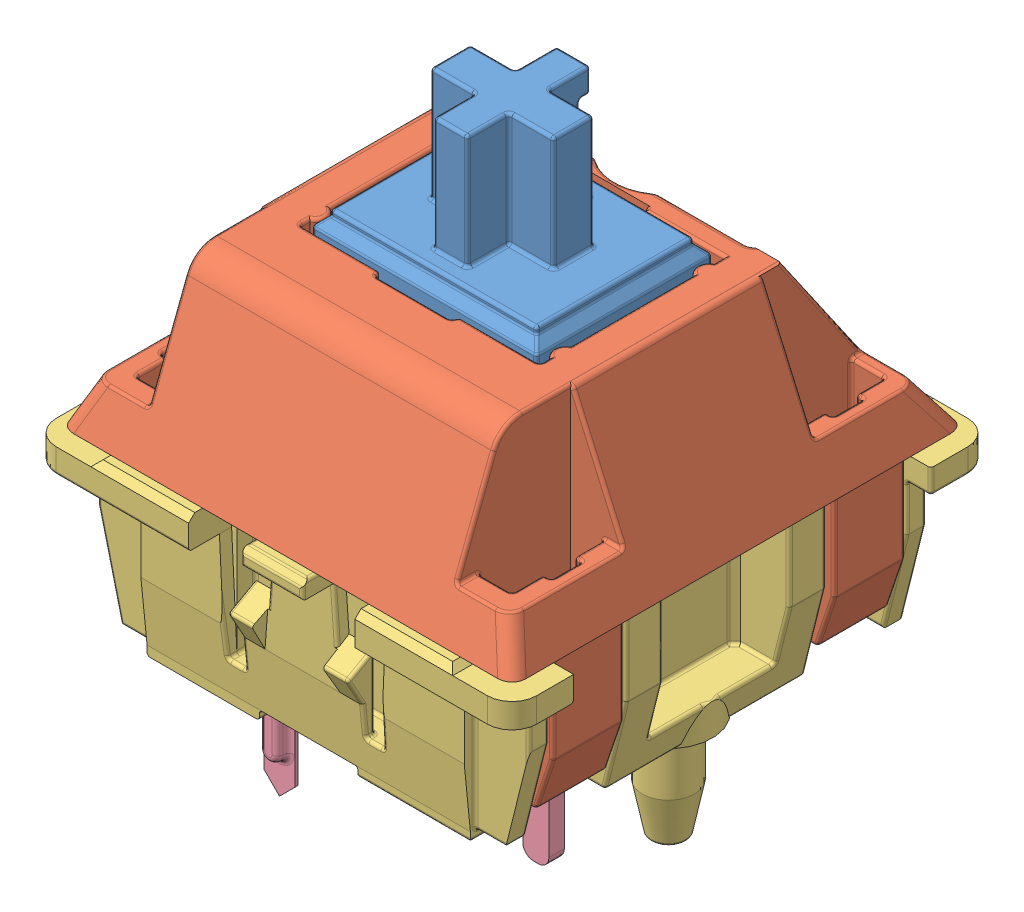
SolidWorks assembly MX_Switch, configuration Default. Lengths in mm.
Overall size (15.6 18.6 15.6).
4 component instances, 4 part files, 9 mates.
Components (placement in the parent):
- MX_Cross-1: MX_Cross [Default] at (7.35 2 -7.35) size (8.9 10.4 5.7)
- MX_Housing-1: MX_Housing [Default] at origin size (14.7 9.91 14.7)
- MX_bot-1: MX_bot [默认] at (7.35 -0.2 -7.35) size (15.6 12.5 15.6)
- MX_Pins-2: MX_Pins [默认] at (-5.5727 -8.7 12.741) size (7.15 6.7 2.96)
Mates (geometry in assembly coordinates):
- Distance1: distance = 0.15 mm anti-aligned: plane of MX 轴 轴体-1 through (3.45 1.4 -4.35) normal (0 0 -1); plane of MX_Cross-1 through (3.7 5.2 -4.5) normal (0 0 1)
- Distance2: distance = 0.25 mm anti-aligned: plane of MX 轴 轴体-1 through (3.45 1.4 -10.35) normal (1 0 0); plane of MX_Cross-1 through (3.7 5.2 -10.2) normal (-1 0 0)
- Coincident4: coincident anti-aligned: plane of MX 轴 轴体-1 through (0 0 0) normal (0 -1 0); plane of MX_bot-1 through (7.35 0 -7.35) normal (0 1 0)
- LimitDistance2: limit distance = -0.5 mm aligned: plane of MX_Cross-1 through (7.35 5.7 -7.35) normal (0 1 0); plane of MX 轴 轴体-1 through (0 5.2 0) normal (0 1 0)
- Coincident10: coincident anti-aligned: plane of MX_bot-1 through (10.6 -0.9 -4.95) normal (0 0 1); plane of 针脚-2 through (10.6 -2.5 -4.95) normal (0 0 -1)
- Coincident11: coincident anti-aligned: plane of MX_bot-1 through (10.6 -0.9 -4.95) normal (1 0 0); plane of 针脚-2 through (10.6 -2.5 -4.95) normal (-1 0 0)
- Concentric1: concentric anti-aligned: cylinder of MX 轴 轴体-1 through (7.35 0.5 -12.292) axis (0 1 0) radius 1.6; cylinder of MX_LED-1 through (7.35 5.8 -12.292) axis (0 -1 0) radius 1.5
- Coincident12: coincident anti-aligned: plane of MX 轴 轴体-1 through (7.35 0.5 -12.292) normal (0 1 0); plane of MX_LED-1 through (7.35 0.5 -12.292) normal (0 -1 0)
- Coincident21: coincident anti-aligned: circle of MX_LED-1; circle of MX_LED Pins-1
